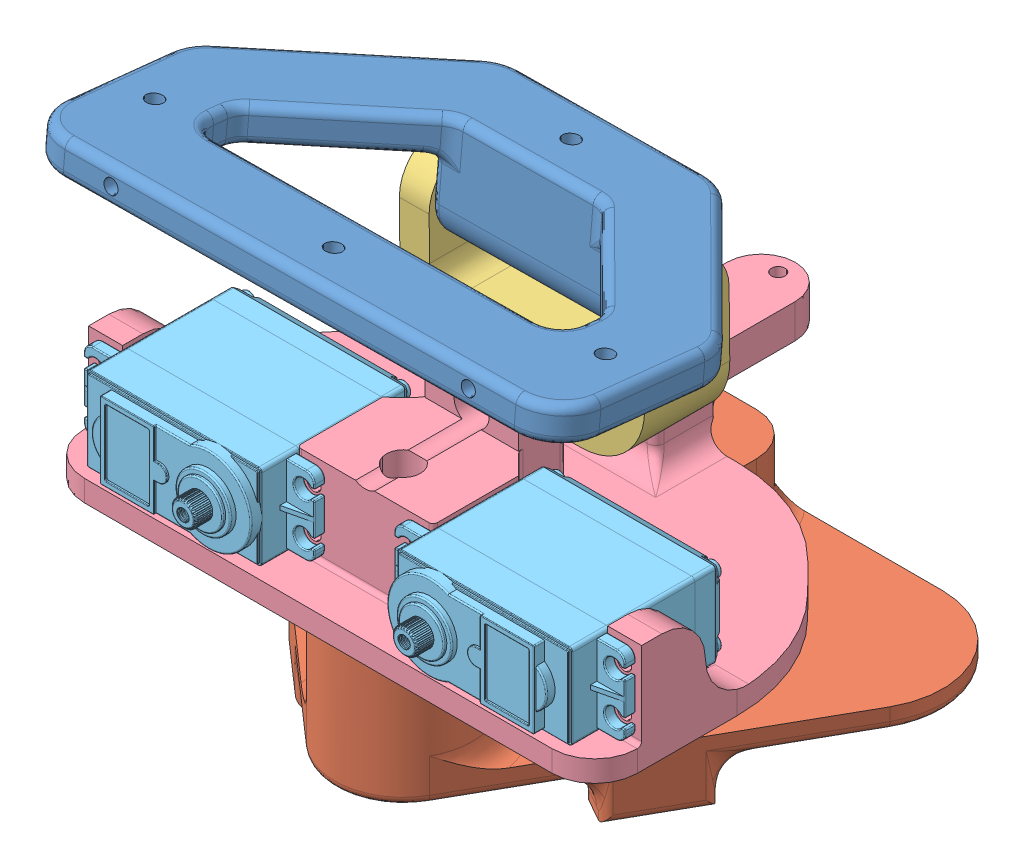
SolidWorks assembly Assem1, configuration Default. Lengths in mm.
Overall size (135.06 121.83 120.56).
7 component instances, 5 part files, 15 mates.
Components (placement in the parent):
- Part_1-1: Part_1 [Default] at (-0.3945 99.3094 -11.17) x (0.999942 0.01077 0.000659) z (-0.001757 0.102279 0.994754) size (126 26 76)
- Part_4-1: Part_4 [Default] at origin size (125.72 43 107.15)
- Part_2-1: Part_2 [Default] at (-0.1096 74.4993 -38.0001) x (0.999942 0.01077 0.000659) z (0.000659 0 -1) size (57.5 40 20)
- Part_3-1: Part_3 [Default] at (0.0132 33 -20) x (1 0 0.000659) z (-0.000659 0 1) size (130 38 112)
- MG995-MG996R Servo-1: MG995-MG996R Servo [Default] at (-34 -7.8 -70.5) x (0 0 1) z (0 1 0) size (20.04 54.2 44.6)
- MG995-MG996R Servo-2: MG995-MG996R Servo [Default] at (-36.4876 48 -18.8241) x (0 -1 0) z (-0.000659 0 1) size (20.04 54.2 44.6)
- MG995-MG996R Servo-3: MG995-MG996R Servo [Default] at (36.5124 48 -18.7759) x (0 1 0) z (-0.000659 0 1) size (20.04 54.2 44.6)
Mates (geometry in assembly coordinates):
- Concentric1: concentric aligned: cylinder of Part_4-1 through (0 5 0) axis (0 -1 0) radius 4.15; cylinder of Part_3-1 through (0 38 0) axis (0 -1 0) radius 4
- Distance3: distance = 0.25 mm anti-aligned: plane of Part_2-1 through (-0.103 74.4993 -48.0001) normal (0.000659 0 -1); plane of Part_3-1 through (0.0318 71 -48.25) normal (-0.000659 0 1)
- Concentric2: concentric anti-aligned: cylinder of Part_2-1 through (0.0316 62 -48) axis (-0.000659 0 1) radius 3.15; cylinder of Part_3-1 through (-0.0132 62 20) axis (0.000659 0 -1) radius 4.15
- Concentric3: concentric aligned: cylinder of Part_1-1 through (62.7575 87.1771 -37.9586) axis (-0.999942 -0.01077 -0.000659) radius 4.15; cylinder of Part_2-1 through (28.5095 86.8082 -37.9812) axis (-0.999942 -0.01077 -0.000659) radius 4.15
- Distance2: distance = 0.25 mm anti-aligned: plane of Part_1-1 through (-21.67 79.3322 -27.2485) normal (-0.999942 -0.01077 -0.000659); plane of Part_2-1 through (-21.8517 74.265 -48.0144) normal (0.999942 0.01077 0.000659)
- Coincident6: coincident anti-aligned: plane of Part_4-1 through (0 33 0) normal (0 1 0); plane of Part_3-1 through (0.0132 33 -20) normal (0 -1 0)
- Coincident7: coincident anti-aligned: plane of Part_4-1 through (0 20 0) normal (0 1 0); plane of MG995-MG996R Servo-1 through (-58.4 20 -75.5) normal (0 -1 0)
- Coincident8: coincident anti-aligned: plane of Part_3-1 through (0.0132 38 -20) normal (0 1 0); plane of MG995-MG996R Servo-2 through (-57.0056 38 8.4624) normal (0 -1 0)
- Coincident9: coincident anti-aligned: plane of Part_3-1 through (-0.0059 58.5 9) normal (-0.000659 0 1); plane of MG995-MG996R Servo-2 through (-60.9059 53 8.9599) normal (0.000659 0 -1)
- Coincident10: coincident anti-aligned: plane of Part_3-1 through (-15.9868 58.5 -20.0105) normal (-1 0 -0.000659); plane of MG995-MG996R Servo-2 through (-16.0056 38 8.4895) normal (1 0 0.000659)
- Coincident11: coincident anti-aligned: plane of Part_3-1 through (0.0132 38 -20) normal (0 1 0); plane of MG995-MG996R Servo-3 through (15.9944 38 8.5105) normal (0 -1 0)
- Coincident12: coincident anti-aligned: plane of Part_3-1 through (16.0132 58.5 -19.9894) normal (1 0 0.000659); plane of MG995-MG996R Servo-3 through (15.9944 58 8.5105) normal (-1 0 -0.000659)
- Coincident13: coincident anti-aligned: plane of Part_3-1 through (-0.0059 58.5 9) normal (-0.000659 0 1); plane of MG995-MG996R Servo-3 through (60.8941 43 9.0401) normal (0.000659 0 -1)
- Coincident14: coincident anti-aligned: plane of Part_4-1 through (-54.5 5 0) normal (1 0 0); plane of MG995-MG996R Servo-1 through (-54.5 19.5 -80.5) normal (-1 0 0)
- Distance1: distance = 0.5 mm anti-aligned: plane of MG995-MG996R Servo-1 through (-13.5 19.5 -80.5) normal (0 0 -1); plane of Part_4-1 through (0 5 -81) normal (0 0 1)
